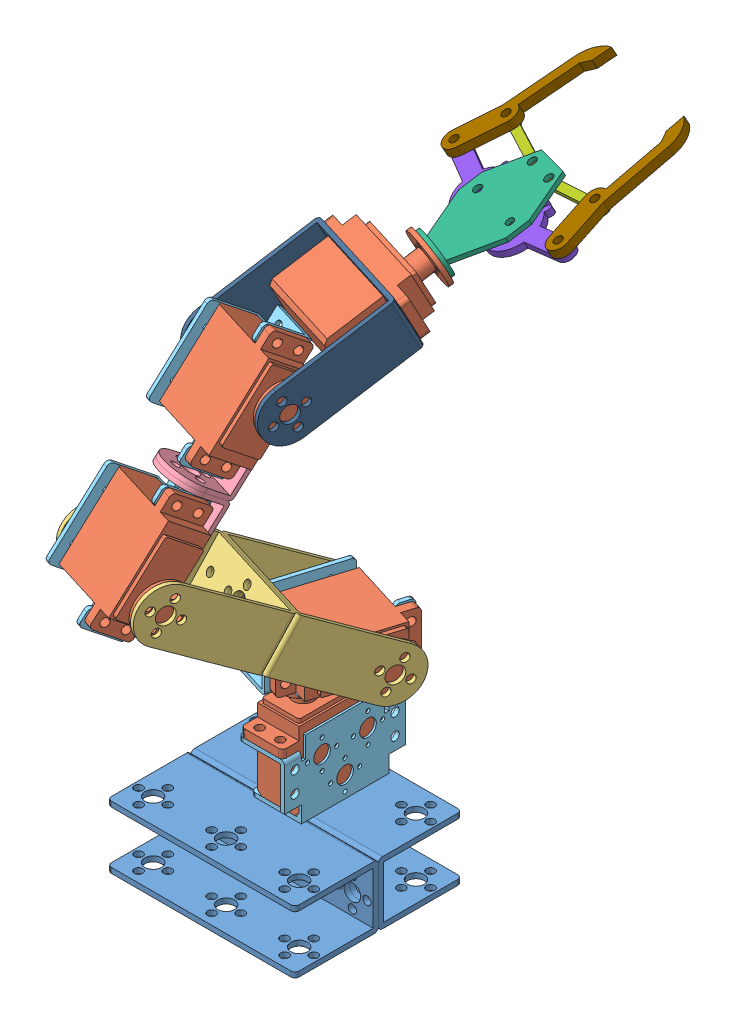
SolidWorks assembly LittleRA, configuration 默认. Lengths in mm.
Overall size (152.7 305.15 239.59).
24 component instances, 10 part files, 43 mates.
Components (placement in the parent):
- base-1: base [默认] at (0.8608 -13.2305 90) size (90 30 40)
- base-2: base [默认] at (0.8608 -13.2305 50) x (-1 0 0) z (0 0 -1) size (90 30 40)
- MG996-1: MG996 [默认] at (3.4971 68.7695 49.945) x (-0.295573 0 0.95532) z (-0.95532 0 -0.295573) size (56 24 49)
- link1-1: link1 [默认] at (30.6239 101.3322 67.1494) x (-0.95532 0 -0.295573) z (-0.153556 -0.854459 0.496308) size (56 64 25)
- link3-1: link3 [默认] at (-10.1327 148.774 100.7644) x (-0.169619 -0.81895 0.548225) z (-0.95532 0 -0.295573) size (35 25 25)
- link2-1: link2 [默认] at (12.8608 34.7695 53) x (0 0 -1) z (0 1 0) size (58 24 36)
- link2-3: link2 [默认] at (-20.1228 131.7001 112.7536) x (0.169619 0.81895 -0.548225) z (0.95532 0 0.295573) size (58 24 36)
- MG996-2: MG996 [默认] at (-21.2151 144.5702 129.8172) x (0.169619 0.81895 -0.548225) z (-0.95532 0 -0.295573) size (56 24 49)
- MG996-3: MG996 [默认] at (-8.1392 38.7695 54) x (0 0 -1) z (0 -1 0) size (56 24 49)
- link2-4: link2 [默认] at (-0.6198 67.7695 49.718) x (0.295573 0 -0.95532) z (0.95532 0 0.295573) size (58 24 36)
- link1-2: link1 [默认] at (-35.8806 128.0874 92.6358) x (0.95532 0 0.295573) z (-0.153556 -0.854459 0.496308) size (56 64 25)
- jaw-1: jaw [默认] at (23.6381 232.4311 22.0631) x (-0.922842 -0.1408 -0.358523) z (0.27966 -0.884977 -0.372299) size (112.18 96.34 20)
  - part1-1: part1 [默认] at origin size (40 52 20)
  - part2-1: part2 [默认] at (21.8064 49.4022 1) x (0.987093 0.160147 0) z (0 0 1) size (36 6 2)
  - part3-1: part3 [默认] at (-13.7 27 1) x (0.971614 -0.236572 0) z (0 0 1) size (48.96 26.8 3)
  - part4-1: part4 [默认] at (-39.6186 43.5612 -3) x (0.322985 0.946404 0) z (0 0 1) size (66.62 17.14 4)
  - part2-2: part2 [默认] at (-21.6944 50.0126 1) x (0.979624 -0.200841 0) z (0 0 1) size (36 6 2)
  - part3-2: part3 [默认] at (13.7 27 4) x (-0.980529 -0.196373 0) z (0 0 -1) size (48.96 26.8 3)
  - part4-2: part4 [默认] at (39.8643 42.3478 1) x (-0.325154 0.945661 0) z (0 0 -1) size (66.62 17.14 4)
- link3-2: link3 [默认] at (-6.3163 167.2004 88.4293) x (0.169619 0.81895 -0.548225) z (0.95532 0 0.295573) size (35 25 25)
- MG996-4: MG996 [默认] at (-5.0095 187.9626 77.439) x (-0.169619 -0.81895 0.548225) z (-0.95532 0 -0.295573) size (56 24 49)
- link2-5: link2 [默认] at (-8.7583 186.5698 76.0226) x (0.169619 0.81895 -0.548225) z (0.95532 0 0.295573) size (58 24 36)
- MG996-5: MG996 [默认] at (7.0026 228.5208 48.7646) x (-0.95532 0 -0.295573) z (-0.264865 -0.443838 0.856069) size (56 24 49)
- link4-1: link4 [默认] at (31.7723 202.0489 63.4379) x (-0.95532 0 -0.295573) z (-0.131186 0.896107 0.424007) size (56 64 25)
Mates (geometry in assembly coordinates):
- 重合1: coincident anti-aligned: plane of part1-1 through (-44.1392 16.7695 70) normal (0 0 -1); plane of part1-2 through (45.8608 16.7695 70) normal (0 0 1)
- 同心1: concentric anti-aligned: cylinder of part1-1 through (0.8608 -0.7305 110.001) axis (0 0 -1) radius 4; cylinder of part1-2 through (0.8608 -0.7305 29.999) axis (0 0 1) radius 4
- 同心2: concentric anti-aligned: cylinder of part1-1 through (35.8608 -0.7305 110.001) axis (0 0 -1) radius 4; cylinder of part1-2 through (35.8608 -0.7305 29.999) axis (0 0 1) radius 4
- 重合2: coincident anti-aligned: plane of part1-2 through (0.8608 16.7695 50) normal (0 1 0); plane of part4-1 through (10.8608 16.7695 74) normal (0 -1 0)
- 同心3: concentric anti-aligned: cylinder of part1-2 through (0.8608 -13.2315 42) axis (0 1 0) radius 4; cylinder of part4-1 through (0.8608 18.7695 42) axis (0 -1 0) radius 1
- 同心4: concentric anti-aligned: cylinder of part1-2 through (0.8608 -13.2315 35) axis (0 1 0) radius 2; cylinder of part4-1 through (0.8608 18.7695 35) axis (0 -1 0) radius 1
- 重合3: coincident anti-aligned: plane of part4-1 through (10.8608 46.7695 82) normal (0 1 0); plane of MG996-3 through (11.8608 46.7695 82) normal (0 -1 0)
- 同心5: concentric aligned: cylinder of part4-1 through (6.8608 44.7695 78) axis (0 1 0) radius 2; cylinder of MG996-3 through (6.8608 18.7685 78) axis (0 1 0) radius 2
- 同心8: concentric aligned: cylinder of part4-1 through (-3.1392 44.7695 78) axis (0 1 0) radius 2; cylinder of MG996-3 through (-3.1392 18.7685 78) axis (0 1 0) radius 2
- 重合4: coincident anti-aligned: plane of MG996-3 through (1.8608 67.7695 62) normal (0 1 0); plane of link2-4 through (-0.6198 67.7695 49.718) normal (0 -1 0)
- 重合5: coincident anti-aligned: plane of MG996-1 through (19.4157 88.7695 25.5606) normal (-0.95532 0 -0.295573); plane of link2-4 through (19.4157 69.7695 25.5606) normal (0.95532 0 0.295573)
- 同心13: concentric aligned: cylinder of MG996-1 through (-8.5166 83.7695 21.1056) axis (0.95532 0 0.295573) radius 2; cylinder of link2-4 through (16.3227 83.7695 28.7908) axis (0.95532 0 0.295573) radius 2
- 同心14: concentric aligned: cylinder of MG996-1 through (-8.5166 73.7695 21.1056) axis (0.95532 0 0.295573) radius 2; cylinder of link2-4 through (16.3227 73.7695 28.7908) axis (0.95532 0 0.295573) radius 2
- 同心15: concentric aligned: cylinder of MG996-3 through (1.8608 65.7695 62) axis (0 -1 0) radius 5; cylinder of part4-4 through (1.8608 69.7695 62) axis (0 -1 0) radius 4
- 重合6: coincident anti-aligned: plane of MG996-1 through (33.5659 78.7695 50.8741) normal (0.95532 0 0.295573); plane of link1-1 through (35.3084 60.5548 45.2423) normal (-0.95532 0 -0.295573)
- 同心16: concentric anti-aligned: cylinder of MG996-1 through (31.6553 78.7695 50.2829) axis (-0.95532 0 -0.295573) radius 5; cylinder of link1-1 through (-18.0214 78.7695 34.9131) axis (0.95532 0 0.295573) radius 4
- 重合8: coincident anti-aligned: plane of link1-1 through (-32.9474 94.844 83.1555) normal (-0.252555 0.51952 0.816282); plane of link1-2 through (20.5505 94.844 99.7076) normal (0.252555 -0.51952 -0.816282)
- 同心19: concentric anti-aligned: cylinder of link1-1 through (-4.2792 105.5252 85.2285) axis (0.252555 -0.51952 -0.816282) radius 4; cylinder of link1-2 through (-4.2787 105.5242 85.2269) axis (-0.252555 0.51952 0.816282) radius 4
- 同心20: concentric anti-aligned: cylinder of link1-1 through (-23.3856 105.5252 79.317) axis (0.252555 -0.51952 -0.816282) radius 2; cylinder of link1-2 through (-23.3851 105.5242 79.3154) axis (-0.252555 0.51952 0.816282) radius 2
- 重合9: coincident anti-aligned: plane of link2-3 through (-4.2241 156.5974 101.9667) normal (0.95532 0 0.295573); plane of MG996-2 through (-3.9821 156.0235 101.1844) normal (-0.95532 0 -0.295573)
- 同心21: concentric aligned: cylinder of link2-3 through (-7.7815 155.6171 106.6979) axis (0.95532 0 0.295573) radius 2; cylinder of MG996-2 through (-32.6208 155.6171 99.0127) axis (0.95532 0 0.295573) radius 2
- 同心22: concentric aligned: cylinder of link2-3 through (-10.2021 161.3557 114.5215) axis (0.95532 0 0.295573) radius 2; cylinder of MG996-2 through (-35.0414 161.3557 106.8363) axis (0.95532 0 0.295573) radius 2
- 重合10: coincident anti-aligned: plane of MG996-2 through (7.5528 132.28 134.9511) normal (0.95532 0 0.295573); plane of link1-2 through (1.9711 129.1314 152.9915) normal (-0.95532 0 -0.295573)
- 同心23: concentric aligned: cylinder of MG996-2 through (5.6421 132.28 134.3599) axis (-0.95532 0 -0.295573) radius 5; cylinder of link1-2 through (9.4634 132.28 135.5422) axis (-0.95532 0 -0.295573) radius 4
- 重合11: coincident anti-aligned: plane of link3-1 through (-12.5251 140.7086 108.4966) normal (-0.242059 0.573865 0.78236); plane of link2-3 through (-20.1228 131.7001 112.7536) normal (0.242059 -0.573865 -0.78236)
- 同心24: concentric aligned: cylinder of link3-1 through (-13.7124 134.9759 112.3342) axis (0.242059 -0.573865 -0.78236) radius 2; cylinder of link2-3 through (-14.1965 136.1236 113.8989) axis (0.242059 -0.573865 -0.78236) radius 1
- 同心25: concentric aligned: cylinder of link3-1 through (-12.5251 140.7086 108.4966) axis (0.242059 -0.573865 -0.78236) radius 4; cylinder of link2-3 through (-13.0092 141.8563 110.0613) axis (0.242059 -0.573865 -0.78236) radius 4
- 同心26: concentric anti-aligned: cylinder of link3-1 through (-11.5895 163.5226 105.4728) axis (0.169619 0.81895 -0.548225) radius 4; cylinder of link3-2 through (-10.911 166.7984 103.2799) axis (-0.169619 -0.81895 0.548225) radius 4
- 重合12: coincident anti-aligned: plane of link3-1 through (3.2329 159.1349 99.8562) normal (0.169619 0.81895 -0.548225); plane of link3-2 through (-20.6501 159.1349 92.4669) normal (-0.169619 -0.81895 0.548225)
- 同心27: concentric anti-aligned: cylinder of link3-1 through (-13.2839 167.5397 110.9493) axis (0.169619 0.81895 -0.548225) radius 2; cylinder of link3-2 through (-12.6054 170.8155 108.7564) axis (-0.169619 -0.81895 0.548225) radius 2
- 重合13: coincident anti-aligned: plane of link3-2 through (-4.8922 177.5613 83.8265) normal (-0.242059 0.573865 0.78236); plane of link2-5 through (-8.7583 186.5698 76.0226) normal (0.242059 -0.573865 -0.78236)
- 同心28: concentric aligned: cylinder of link3-2 through (1.795 177.5613 85.8955) axis (0.242059 -0.573865 -0.78236) radius 2; cylinder of link2-5 through (1.3109 178.7091 87.4602) axis (0.242059 -0.573865 -0.78236) radius 1
- 同心29: concentric aligned: cylinder of link3-2 through (-4.8922 177.5613 83.8265) axis (0.242059 -0.573865 -0.78236) radius 4; cylinder of link2-5 through (-5.3763 178.7091 85.3912) axis (0.242059 -0.573865 -0.78236) radius 4
- 重合16: coincident anti-aligned: plane of MG996-4 through (2.5412 222.3705 80.1005) normal (-0.95532 0 -0.295573); plane of link2-5 through (7.1403 211.4671 65.2357) normal (0.95532 0 0.295573)
- 同心33: concentric aligned: cylinder of MG996-4 through (-23.6769 216.2254 70.1053) axis (0.95532 0 0.295573) radius 2; cylinder of link2-5 through (1.1624 216.2254 77.7905) axis (0.95532 0 0.295573) radius 2
- 同心34: concentric aligned: cylinder of MG996-4 through (-21.2563 210.4867 62.2817) axis (0.95532 0 0.295573) radius 2; cylinder of link2-5 through (3.583 210.4867 69.9669) axis (0.95532 0 0.295573) radius 2
- 重合17: coincident anti-aligned: plane of MG996-4 through (21.6311 200.2528 89.4484) normal (0.95532 0 0.295573); plane of link4-1 through (16.1506 205.0194 107.1619) normal (-0.95532 0 -0.295573)
- 同心35: concentric anti-aligned: cylinder of MG996-4 through (21.6311 200.2528 89.4484) axis (-0.95532 0 -0.295573) radius 12; cylinder of link4-1 through (-29.9561 200.2528 73.4875) axis (0.95532 0 0.295573) radius 4
- 重合18: coincident anti-aligned: plane of MG996-5 through (-15.0037 214.1494 25.1598) normal (-0.264865 -0.443838 0.856069); plane of link4-1 through (-17.9554 234.3118 34.7) normal (0.264865 0.443838 -0.856069)
- 同心36: concentric aligned: cylinder of MG996-5 through (-20.5667 215.1631 56.673) axis (0.264865 0.443838 -0.856069) radius 2; cylinder of link4-1 through (-30.1019 199.185 87.4915) axis (0.264865 0.443838 -0.856069) radius 2
- 同心37: concentric aligned: cylinder of MG996-5 through (-19.2549 206.202 52.433) axis (0.264865 0.443838 -0.856069) radius 2; cylinder of link4-1 through (-28.79 190.2239 83.2515) axis (0.264865 0.443838 -0.856069) radius 2
- 重合19: coincident anti-aligned: plane of jaw-1/part1-1 through (23.6381 232.4311 22.0631) normal (-0.264865 -0.443838 0.856069); plane of MG996-5 through (23.6381 232.4311 22.0631) normal (0.264865 0.443838 -0.856069)
- 同心38: concentric aligned: cylinder of jaw-1/part1-1 through (24.1678 233.3187 20.3509) axis (-0.264865 -0.443838 0.856069) radius 10; cylinder of MG996-5 through (23.6381 232.4311 22.0631) axis (-0.264865 -0.443838 0.856069) radius 12
